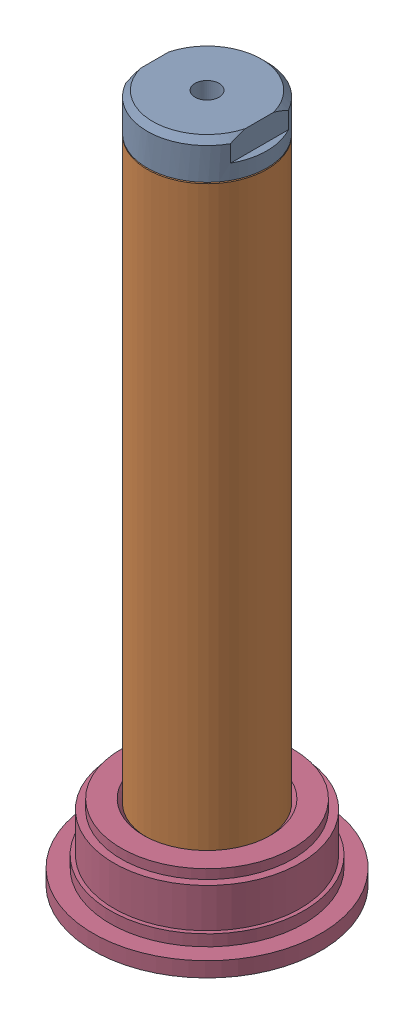
SolidWorks assembly BA-F33R2-3, configuration Default. Lengths in mm.
Overall size (48.34 146.08 48.34).
8 component instances, 5 part files, 0 mates.
Components (placement in the parent):
- BLB-10-1: BLB-10 [Default] at origin size (25.4 134.16 25.4)
  - BLB-ASM10-1: BLB-ASM10 [Default] at origin size (25.4 134.16 25.4)
    - BS-18-33R-1: BS-18-33R [Default] at origin size (25.4 12.7 25.4)
    - BT-33R-SM-1: BT-33R-SM [Default] at (0 -121.4628 0) size (25.4 126.21 25.4)
    - RNG18COP-1: RNG18COP [Default] at (0 -0.5842 0) size (24.13 1.07 24.12)
- BB-18-33FR2-3-1: BB-18-33FR2-3 [Default] at (0 -134.1628 0) size (48.34 15.88 48.34)
  - FORGING-2522-1: FORGING-2522 [Default] at origin size (48.34 15.88 48.34)
- RNGSIL18-33-1: RNGSIL18-33 [Default] at (0 -120.9548 0) size (24.13 1.07 24.12)
